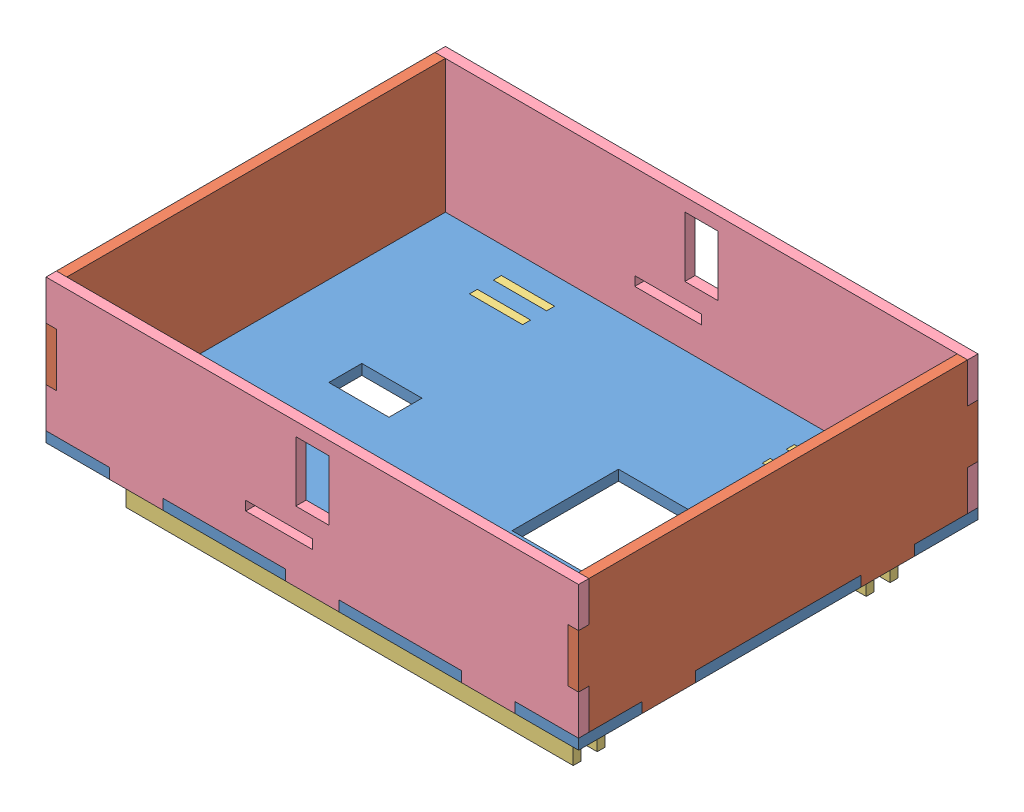
SolidWorks assembly Chassis Assembly, configuration Default. Lengths in mm.
Overall size (200 73.9 150).
9 component instances, 4 part files, 25 mates.
Components (placement in the parent):
- Chassis Base-1: Chassis Base [Default] at (112.1191 114.2201 193.0111)
- Chassis Short Side-1: Chassis Short Side [Default] at (208.2191 143.1201 193.0111) x (0 0 -1) z (0 -1 0) size (150 3.9 53.9)
- Chassis Short Side-2: Chassis Short Side [Default] at (12.1191 143.1201 193.0111) x (0 0 -1) z (0 -1 0) size (150 3.9 53.9)
- Lift Axle Track-1: Lift Axle Track [Default] at (196.1191 114.2201 251.0111) x (-1 0 0) z (0 1 0) size (168 3 23.9)
- Lift Axle Track-2: Lift Axle Track [Default] at (196.1191 114.2201 141.0111) x (-1 0 0) z (0 1 0) size (168 3 23.9)
- Lift Axle Track-3: Lift Axle Track [Default] at (196.1191 114.2201 132.0111) x (-1 0 0) z (0 1 0) size (168 3 23.9)
- Lift Axle Track-4: Lift Axle Track [Default] at (196.1191 114.2201 242.0111) x (-1 0 0) z (0 1 0) size (168 3 23.9)
- Chassis Wide Side-1: Chassis Wide Side [Default] at (112.1191 143.1201 121.9111) x (1 0 0) z (0 1 0) size (200 3.9 53.9)
- Chassis Wide Side-2: Chassis Wide Side [Default] at (112.1191 143.1201 268.0111) x (1 0 0) z (0 1 0) size (200 3.9 53.9)
Mates (geometry in assembly coordinates):
- Coincident3: coincident: plane of Chassis Base-1 through (208.2191 118.1201 244.1111) normal (1 0 0); plane of Chassis Short Side-1 through (208.2191 143.1201 193.0111) normal (-1 0 0)
- Coincident6: coincident: plane of Chassis Base-1 through (12.1191 118.1201 161.9111) normal (-1 0 0); plane of Chassis Short Side-2 through (12.1191 143.1201 193.0111) normal (-1 0 0)
- Coincident8: coincident: plane of Chassis Base-1 through (112.1191 118.1201 193.0111) normal (0 1 0); plane of Lift Axle Track-1 through (47.1191 118.1201 254.0111) normal (0 1 0)
- Coincident10: coincident: plane of Chassis Base-1 through (112.1191 118.1201 193.0111) normal (0 1 0); plane of Lift Axle Track-2 through (177.1191 118.1201 144.0111) normal (0 1 0)
- Coincident11: coincident: plane of Chassis Base-1 through (112.1191 118.1201 193.0111) normal (0 1 0); plane of Lift Axle Track-3 through (177.1191 118.1201 135.0111) normal (0 1 0)
- Coincident12: coincident: plane of Chassis Base-1 through (112.1191 118.1201 193.0111) normal (0 1 0); plane of Lift Axle Track-4 through (47.1191 118.1201 245.0111) normal (0 1 0)
- Coincident13: coincident: plane of Chassis Base-1 through (177.1191 118.1201 254.0111) normal (0 0 -1); plane of Lift Axle Track-1 through (196.1191 114.2201 254.0111) normal (0 0 1)
- Coincident14: coincident: plane of Chassis Base-1 through (157.1191 118.1201 251.0111) normal (1 0 0); plane of Lift Axle Track-1 through (157.1191 114.2201 254.0111) normal (-1 0 0)
- Coincident15: coincident: plane of Chassis Base-1 through (177.1191 118.1201 245.0111) normal (0 0 -1); plane of Lift Axle Track-4 through (196.1191 114.2201 245.0111) normal (0 0 1)
- Coincident16: coincident: plane of Chassis Base-1 through (157.1191 118.1201 245.0111) normal (1 0 0); plane of Lift Axle Track-4 through (157.1191 114.2201 245.0111) normal (-1 0 0)
- Coincident17: coincident: plane of Chassis Base-1 through (47.1191 118.1201 132.0111) normal (0 0 1); plane of Lift Axle Track-3 through (196.1191 114.2201 132.0111) normal (0 0 -1)
- Coincident19: coincident: plane of Chassis Base-1 through (47.1191 118.1201 135.0111) normal (1 0 0); plane of Lift Axle Track-3 through (47.1191 114.2201 135.0111) normal (-1 0 0)
- Coincident20: coincident: plane of Chassis Base-1 through (47.1191 118.1201 141.0111) normal (0 0 1); plane of Lift Axle Track-2 through (196.1191 114.2201 141.0111) normal (0 0 -1)
- Coincident21: coincident: plane of Chassis Base-1 through (47.1191 118.1201 141.0111) normal (1 0 0); plane of Lift Axle Track-2 through (47.1191 114.2201 144.0111) normal (-1 0 0)
- Coincident22: coincident: plane of Chassis Base-1 through (112.1191 118.1201 193.0111) normal (0 1 0); plane of Chassis Wide Side-2 through (112.1191 118.1201 264.1111) normal (0 -1 0)
- Coincident23: coincident: plane of Chassis Base-1 through (36.0191 118.1201 264.1111) normal (0 0 1); plane of Chassis Wide Side-2 through (112.1191 143.1201 264.1111) normal (0 0 -1)
- Coincident24: coincident: plane of Chassis Base-1 through (56.0191 118.1201 268.0111) normal (-1 0 0); plane of Chassis Wide Side-2 through (56.0191 143.1201 264.1111) normal (1 0 0)
- Coincident26: coincident: plane of Chassis Base-1 through (102.1191 118.1201 121.9111) normal (0 0 -1); plane of Chassis Wide Side-1 through (112.1191 143.1201 121.9111) normal (0 0 1)
- Coincident27: coincident: plane of Chassis Base-1 through (112.1191 118.1201 193.0111) normal (0 1 0); plane of Chassis Wide Side-1 through (112.1191 118.1201 118.0111) normal (0 -1 0)
- Coincident28: coincident: plane of Chassis Base-1 through (102.1191 118.1201 121.9111) normal (1 0 0); plane of Chassis Wide Side-1 through (102.1191 143.1201 118.0111) normal (-1 0 0)
- Coincident30: coincident: plane of Chassis Base-1 through (112.1191 114.2201 193.0111) normal (0 -1 0); plane of Chassis Short Side-2 through (16.0191 114.2201 244.1111) normal (0 -1 0)
- Coincident33: coincident aligned: plane of Chassis Short Side-2 through (16.0191 153.1201 268.0111) normal (0 0 1); plane of Chassis Wide Side-2 through (112.1191 143.1201 268.0111) normal (0 0 1)
- Coincident35: coincident aligned: plane of Chassis Short Side-1 through (212.1191 143.1201 193.0111) normal (1 0 0); plane of Chassis Wide Side-1 through (212.1191 143.1201 118.0111) normal (1 0 0)
- Coincident36: coincident aligned: plane of Chassis Short Side-1 through (212.1191 153.1201 118.0111) normal (0 0 -1); plane of Chassis Wide Side-1 through (112.1191 143.1201 118.0111) normal (0 0 -1)
- Coincident37: coincident aligned: plane of Chassis Short Side-1 through (212.1191 168.1201 264.1111) normal (0 1 0); plane of Chassis Wide Side-1 through (112.1191 168.1201 118.0111) normal (0 1 0)
